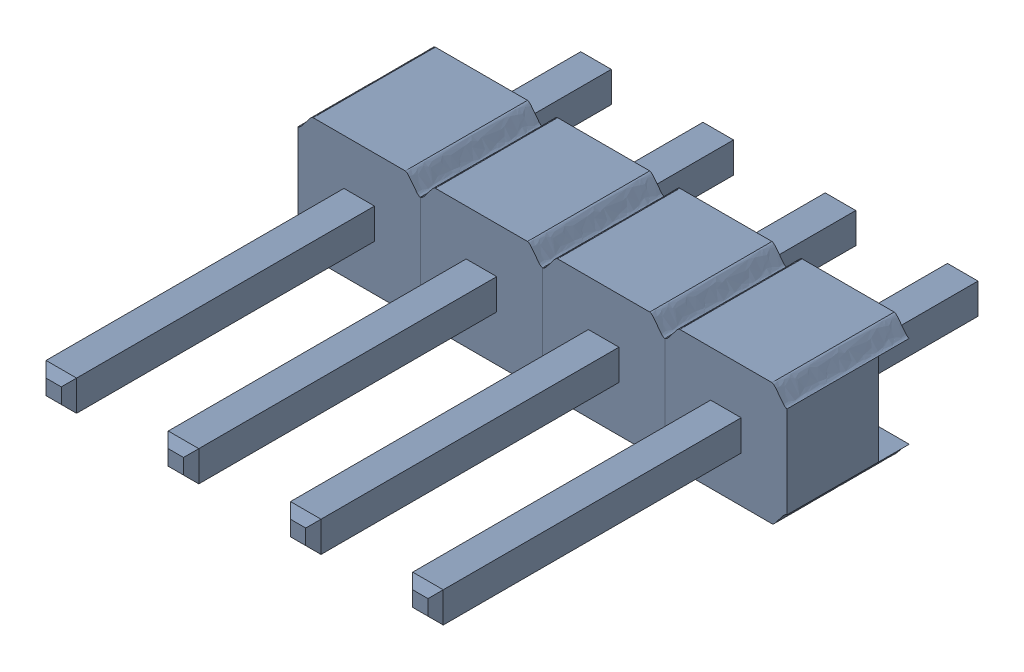
SolidWorks assembly Pin Header 1x4 TH Pitch 2.54mm v2, configuration Default. Lengths in mm.
Overall size (10.16 2.58 11.43).
12 component instances, 2 part files, 0 mates.
Components (placement in the parent):
- asm_pin-1: asm_pin [Default] at origin size (2.54 2.58 11.43)
  - spacer_1-1: spacer_1 [Default] at origin size (2.54 2.58 2.54)
  - pin_1-1: pin_1 [Default] at origin size (0.64 0.64 11.43)
- asm_pin_1-1: asm_pin_1 [Default] at (2.54 0 0) size (2.54 2.58 11.43)
  - spacer_1-1: spacer_1 [Default] at origin size (2.54 2.58 2.54)
  - pin_1-1: pin_1 [Default] at origin size (0.64 0.64 11.43)
- asm_pin_2-1: asm_pin_2 [Default] at (5.08 0 0) size (2.54 2.58 11.43)
  - spacer_1-1: spacer_1 [Default] at origin size (2.54 2.58 2.54)
  - pin_1-1: pin_1 [Default] at origin size (0.64 0.64 11.43)
- asm_pin_3-1: asm_pin_3 [Default] at (7.62 0 0) size (2.54 2.58 11.43)
  - spacer_1-1: spacer_1 [Default] at origin size (2.54 2.58 2.54)
  - pin_1-1: pin_1 [Default] at origin size (0.64 0.64 11.43)
